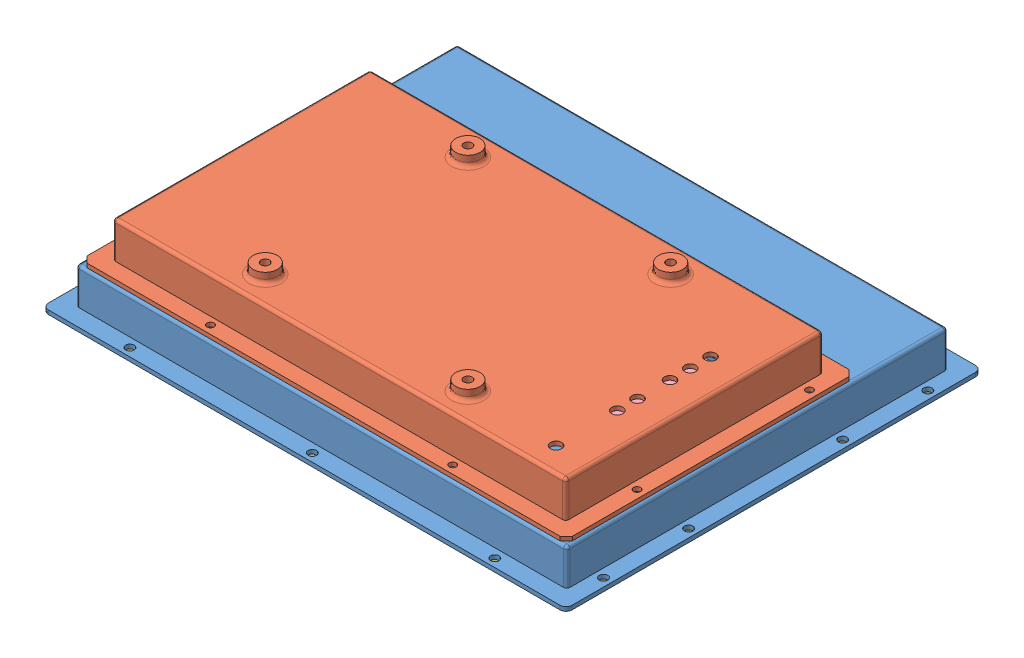
SolidWorks assembly W0000364-00-Assembly fMRI Touchscreen housing, configuration Default. Lengths in mm.
Overall size (258.3 50 205).
5 component instances, 5 part files, 12 mates.
Components (placement in the parent):
- W0000364-01-Boardcase-1: W0000364-01-Boardcase [Default] at (-162.5044 10.886 104.5522) size (258.3 26 205)
- W0000364-02-Buttoncase-1: W0000364-02-Buttoncase [Default] at (-153.1044 50.886 -47.4478) x (1 0 0) z (0 0 -1) size (239.5 25 142.5)
- W0000364-03-Screencase-1: W0000364-03-Screencase [Default] at (-166.3544 3.386 108.8022) size (266 7.5 213.3) (hidden)
- W0000364-04-spacer-1: W0000364-04-spacer [Default] at (-154.2544 5.886 96.4522) size (241.8 3 188.8)
- W0000364-05-touchscreen-1: W0000364-05-touchscreen [Default] at (-145.8544 7.536 88.6022) size (235 5 173)
Mates (geometry in assembly coordinates):
- Coincident2: coincident anti-aligned: plane of W0000364-01-Boardcase-1 through (-162.5044 30.886 104.5522) normal (0 1 0); plane of W0000364-02-Buttoncase-1 through (-153.1044 30.886 -47.4478) normal (0 -1 0)
- Distance2: distance = 1 mm aligned: plane of W0000364-01-Boardcase-1 through (-154.3544 12.886 96.0522) normal (0 0 1); plane of W0000364-02-Buttoncase-1 through (-153.1044 30.886 95.0522) normal (0 0 1)
- Distance1: distance = 1.25 mm aligned: plane of W0000364-01-Boardcase-1 through (87.6456 12.886 96.0522) normal (1 0 0); plane of W0000364-02-Buttoncase-1 through (86.3956 30.886 -47.4478) normal (1 0 0)
- Coincident3: coincident anti-aligned: plane of W0000364-01-Boardcase-1 through (-162.5044 10.886 104.5522) normal (0 -1 0); plane of W0000364-03-Screencase-1 through (-166.3544 10.886 108.8022) normal (0 1 0)
- Coincident4: coincident anti-aligned: plane of W0000364-01-Boardcase-1 through (87.6456 12.886 96.0522) normal (1 0 0); plane of W0000364-03-Screencase-1 through (87.6456 5.886 -92.3478) normal (-1 0 0)
- Coincident5: coincident anti-aligned: plane of W0000364-01-Boardcase-1 through (-154.2544 8.886 -92.3478) normal (0 0 -1); plane of W0000364-03-Screencase-1 through (-154.3544 5.886 -92.3478) normal (0 0 1)
- Coincident6: coincident anti-aligned: plane of W0000364-01-Boardcase-1 through (-162.5044 8.886 104.5522) normal (0 -1 0); plane of W0000364-04-spacer-1 through (-154.2544 8.886 96.4522) normal (0 1 0)
- Coincident7: coincident aligned: plane of W0000364-01-Boardcase-1 through (-154.2544 8.886 -92.3478) normal (-1 0 0); plane of W0000364-04-spacer-1 through (-154.2544 8.886 96.4522) normal (-1 0 0)
- Coincident8: coincident aligned: plane of W0000364-01-Boardcase-1 through (-154.2544 8.886 -92.3478) normal (0 0 -1); plane of W0000364-04-spacer-1 through (-154.2544 8.886 -92.3478) normal (0 0 -1)
- Coincident9: coincident anti-aligned: plane of W0000364-01-Boardcase-1 through (-162.5044 10.286 104.5522) normal (0 -1 0); plane of W0000364-05-touchscreen-1 through (84.1456 10.286 -66.3978) normal (0 1 0)
- Distance4: distance = 0.2 mm anti-aligned: plane of W0000364-01-Boardcase-1 through (-145.8544 295.0114 88.8022) normal (0 0 -1); plane of W0000364-05-touchscreen-1 through (-145.8544 12.536 88.6022) normal (0 0 1)
- Distance3: distance = 0 mm anti-aligned: plane of W0000364-01-Boardcase-1 through (79.1456 295.0114 88.8022) normal (-1 0 0); plane of W0000364-05-touchscreen-1 through (79.1456 12.536 88.6022) normal (1 0 0)
